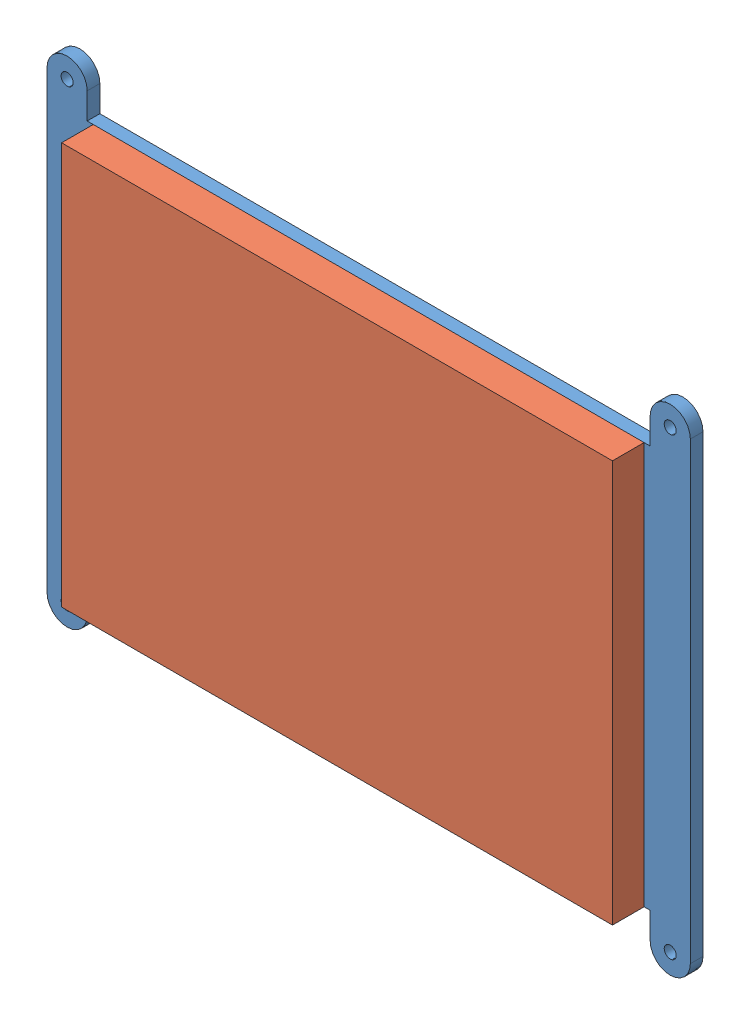
SolidWorks assembly Assem1, configuration Default. Lengths in mm.
Overall size (81.28 62.48 5.6).
2 component instances, 2 part files, 3 mates.
Components (placement in the parent):
- Display_Board-1: Display_Board [Default] at (26.2517 41.3161 64.494) size (81.28 62.48 1.6)
- TFT_LCD_Panel-1: TFT_LCD_Panel [Default] at (26.2537 41.3161 66.094) size (69.6 50.8 4)
Mates (geometry in assembly coordinates):
- Coincident1: coincident: plane of Display_Board-1 through (-11.8483 70.0181 66.094) normal (0 0 1); plane of TFT_LCD_Panel-1 through (25.9606 41.3161 66.094) normal (0 0 -1)
- Coincident8: coincident: plane of Display_Board-1 through (-9.3083 15.9161 66.094) normal (0 -1 0); plane of TFT_LCD_Panel-1 through (-8.8374 15.9161 70.094) normal (0 -1 0)
- Distance1: distance = 0.76 mm anti-aligned: plane of Display_Board-1 through (61.8117 66.7161 66.094) normal (-1 0 0); plane of TFT_LCD_Panel-1 through (61.0517 15.9161 70.094) normal (1 0 0)
